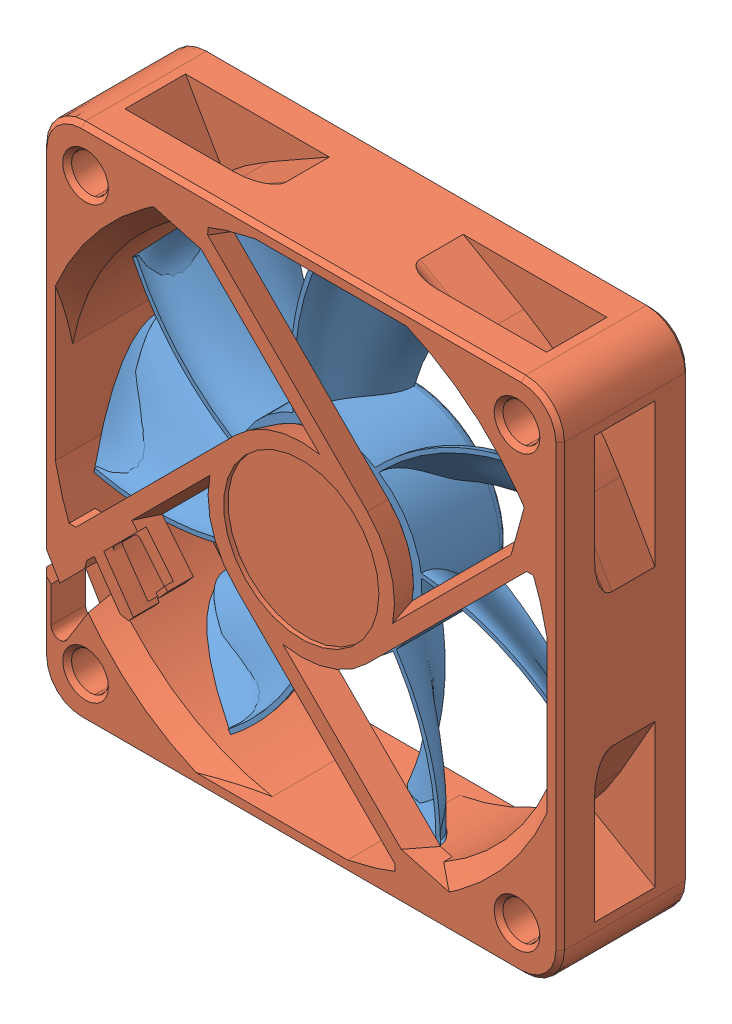
SolidWorks assembly SUNON Fan 60x60x15 mm, configuration Default. Lengths in mm.
Overall size (77.54 77.68 15).
2 component instances, 2 part files, 5 mates.
Components (placement in the parent):
- Fan Wheel-1: Fan Wheel [Default] at (0 0 2) x (-0.508791 0.86089 0) z (0 0 1) size (56.86 56.46 10)
- Fan-Sunont_60x60x15mm-1: Fan-Sunont_60x60x15mm [Default] at origin size (60 60 15)
Mates (geometry in assembly coordinates):
- Coincident2: coincident: plane of Fan-Sunont_60x60x15mm-1 through (0 0 0) normal (0 0 1); plane of assembly through (0 0 0) normal (0 0 1)
- Coincident3: coincident: plane of Fan-Sunont_60x60x15mm-1 through (0 0 0) normal (1 0 0); plane of assembly through (0 0 0) normal (1 0 0)
- Concentric1: concentric: cylinder of Fan Wheel-1 through (0 0 12) axis (0 0 -1) radius 10; circle of Fan-Sunont_60x60x15mm-1
- Coincident4: coincident: plane of Fan Wheel-1 through (0 0 12) normal (0 0 1); plane of Fan-Sunont_60x60x15mm-1 through (0 0 12) normal (0 0 -1)
- Coincident5: coincident: plane of Fan-Sunont_60x60x15mm-1 through (0 0 0) normal (0 1 0); plane of assembly through (0 0 0) normal (0 1 0)
